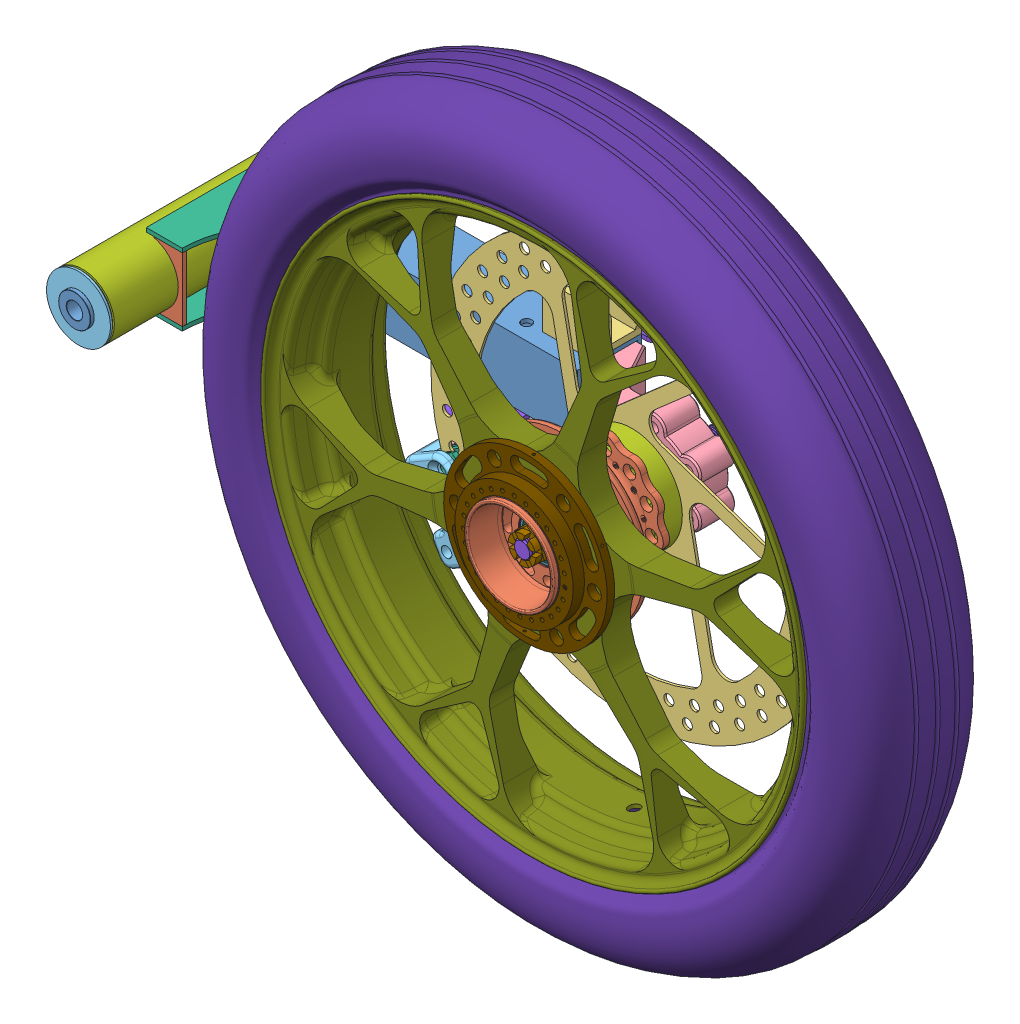
SolidWorks assembly Rear Free Spinning Assembly, configuration Default. Lengths in mm.
Overall size (695.82 635.09 308.21).
71 component instances, 29 part files, 66 mates.
Components (placement in the parent):
- 6338K423_Oil-Embedded Flanged Sleeve Bearing (1)-3: 6338K423_Oil-Embedded Flanged Sleeve Bearing (1) [6338K423] at (-275.5585 98.76 94.6109) size (25.4 25.4 19.05)
- Half Moon Bracket-2: Half Moon Bracket [Default] at (-275.5585 98.76 43.8109) x (1 0 0) z (0 -1 0) size (22.4 3.17 50.8)
- Rear Brake Bracket-2: Rear Brake Bracket [Default] at (-24.3335 128.9225 -60.9641) x (0 0 1) z (1 0 0) size (38.1 36.51 50)
- Rear Cap insert-2: Rear Cap insert [Default] at (-8.8585 76.535 -76.8391) x (0 0 1) z (-1 0 0) size (63.5 83.05 151.54)
- Rear End Cap-3: Rear End Cap [Default] at (-275.5585 98.76 100.9609) x (0 0 -1) z (0.554016 0.832506 0) size (15.88 50.8 50.8)
- Rear Gusset-2: Rear Gusset [Default] at (-50.3286 124.16 -51.4436) x (0 0 1) z (0 1 0) size (127 101.6 3.17)
- Rear Round Tube-2: Rear Round Tube [Default] at (-275.5585 98.76 97.7859) x (0 0 -1) z (1 0 0) size (177.8 50.8 50.8)
- Rear End Cap-4: Rear End Cap [Default] at (-275.5585 98.76 -83.1891) x (0 0 1) z (-0.819378 0.573254 0) size (15.88 50.8 50.8)
- 6338K423_Oil-Embedded Flanged Sleeve Bearing (1)-4: 6338K423_Oil-Embedded Flanged Sleeve Bearing (1) [6338K423] at (-275.5585 98.76 -76.8391) x (-1 0 0) z (0 0 -1) size (25.4 25.4 19.05)
- Longer Spindle_Light-1: Longer Spindle_Light [Default] at (67.3415 98.76 -13.3391) x (0 0 1) z (-0.999407 0.034445 0) size (156.55 34 30)
- 93760A127_Steel Locknut for Use with Cotter Pins-1: 93760A127_Steel Locknut for Use with Cotter Pins [93760A127] at (67.3415 98.76 91.1609) x (0.351034 0.936363 0) z (0 0 1) size (22 25.4 16.76)
- SKF_6004-2Z.stp-2: SKF_6004-2Z.stp [Default] at (67.3415 98.76 29.6609) x (0 0 -1) z (1 0 0) size (12 42 42)
  - SKF_6004-2Z_PART4.stp-1: SKF_6004-2Z_PART4.stp [Default] x (1 0 0) z (0 -0.642788 0.766044)
  - SKF_6004-2Z_PART4.stp-2: SKF_6004-2Z_PART4.stp [Default] x (1 0 0) z (0 -0.984808 0.173648)
  - SKF_6004-2Z_PART4.stp-3: SKF_6004-2Z_PART4.stp [Default] x (1 0 0) z (0 -0.866025 -0.5)
  - SKF_6004-2Z_PART4.stp-4: SKF_6004-2Z_PART4.stp [Default] x (1 0 0) z (0 -0.34202 -0.939693)
  - SKF_6004-2Z_PART4.stp-5: SKF_6004-2Z_PART4.stp [Default] x (1 0 0) z (0 0.34202 -0.939693)
  - SKF_6004-2Z_PART4.stp-6: SKF_6004-2Z_PART4.stp [Default] x (1 0 0) z (0 0.866025 -0.5)
  - SKF_6004-2Z_PART4.stp-7: SKF_6004-2Z_PART4.stp [Default] x (1 0 0) z (0 0.984808 0.173648)
  - SKF_6004-2Z_PART4.stp-8: SKF_6004-2Z_PART4.stp [Default] x (1 0 0) z (0 0.642788 0.766044)
  - SKF_6004-2Z_PART4.stp-9: SKF_6004-2Z_PART4.stp [Default] at origin
  - SKF_6004-2Z_PART3.stp-1: SKF_6004-2Z_PART3.stp [Default] x (1 0 0) z (0 -0.642788 0.766044) size (6.35 6.35 6.35)
  - SKF_6004-2Z_PART3.stp-2: SKF_6004-2Z_PART3.stp [Default] x (1 0 0) z (0 -0.984808 0.173648) size (6.35 6.35 6.35)
  - SKF_6004-2Z_PART3.stp-3: SKF_6004-2Z_PART3.stp [Default] x (1 0 0) z (0 -0.866025 -0.5) size (6.35 6.35 6.35)
  - SKF_6004-2Z_PART3.stp-4: SKF_6004-2Z_PART3.stp [Default] x (1 0 0) z (0 -0.34202 -0.939693) size (6.35 6.35 6.35)
  - SKF_6004-2Z_PART3.stp-5: SKF_6004-2Z_PART3.stp [Default] x (1 0 0) z (0 0.34202 -0.939693) size (6.35 6.35 6.35)
  - SKF_6004-2Z_PART3.stp-6: SKF_6004-2Z_PART3.stp [Default] x (1 0 0) z (0 0.866025 -0.5) size (6.35 6.35 6.35)
  - SKF_6004-2Z_PART3.stp-7: SKF_6004-2Z_PART3.stp [Default] x (1 0 0) z (0 0.984808 0.173648) size (6.35 6.35 6.35)
  - SKF_6004-2Z_PART3.stp-8: SKF_6004-2Z_PART3.stp [Default] x (1 0 0) z (0 0.642788 0.766044) size (6.35 6.35 6.35)
  - SKF_6004-2Z_PART3.stp-9: SKF_6004-2Z_PART3.stp [Default] at origin size (6.35 6.35 6.35)
  - SKF_6004-2Z_PART2.stp-1: SKF_6004-2Z_PART2.stp [Default] at origin size (12 42 42)
  - SKF_6004-2Z_PART1.stp-1: SKF_6004-2Z_PART1.stp [Default] at origin size (12 37.19 37.19)
- SKF_6003-2Z.stp-2: SKF_6003-2Z.stp [Default] at (67.3415 98.76 75.1609) x (0 0 -1) z (-0.882988 0.469396 0) size (10 35 35)
  - SKF_6003-2Z_PART4.stp-1: SKF_6003-2Z_PART4.stp [Default] x (1 0 0) z (0 -0.587785 0.809017)
  - SKF_6003-2Z_PART4.stp-2: SKF_6003-2Z_PART4.stp [Default] x (1 0 0) z (0 -0.951057 0.309017)
  - SKF_6003-2Z_PART4.stp-3: SKF_6003-2Z_PART4.stp [Default] x (1 0 0) z (0 -0.951057 -0.309017)
  - SKF_6003-2Z_PART4.stp-4: SKF_6003-2Z_PART4.stp [Default] x (1 0 0) z (0 -0.587785 -0.809017)
  - SKF_6003-2Z_PART4.stp-5: SKF_6003-2Z_PART4.stp [Default] x (1 0 0) z (0 0 -1)
  - SKF_6003-2Z_PART4.stp-6: SKF_6003-2Z_PART4.stp [Default] x (1 0 0) z (0 0.587785 -0.809017)
  - SKF_6003-2Z_PART4.stp-7: SKF_6003-2Z_PART4.stp [Default] x (1 0 0) z (0 0.951057 -0.309017)
  - SKF_6003-2Z_PART4.stp-8: SKF_6003-2Z_PART4.stp [Default] x (1 0 0) z (0 0.951057 0.309017)
  - SKF_6003-2Z_PART4.stp-9: SKF_6003-2Z_PART4.stp [Default] x (1 0 0) z (0 0.587785 0.809017)
  - SKF_6003-2Z_PART4.stp-10: SKF_6003-2Z_PART4.stp [Default] at origin
  - SKF_6003-2Z_PART3.stp-1: SKF_6003-2Z_PART3.stp [Default] x (1 0 0) z (0 -0.587785 0.809017) size (4.76 4.76 4.76)
  - SKF_6003-2Z_PART3.stp-2: SKF_6003-2Z_PART3.stp [Default] x (1 0 0) z (0 -0.951057 0.309017) size (4.76 4.76 4.76)
  - SKF_6003-2Z_PART3.stp-3: SKF_6003-2Z_PART3.stp [Default] x (1 0 0) z (0 -0.951057 -0.309017) size (4.76 4.76 4.76)
  - SKF_6003-2Z_PART3.stp-4: SKF_6003-2Z_PART3.stp [Default] x (1 0 0) z (0 -0.587785 -0.809017) size (4.76 4.76 4.76)
  - SKF_6003-2Z_PART3.stp-5: SKF_6003-2Z_PART3.stp [Default] x (1 0 0) z (0 0 -1) size (4.76 4.76 4.76)
  - SKF_6003-2Z_PART3.stp-6: SKF_6003-2Z_PART3.stp [Default] x (1 0 0) z (0 0.587785 -0.809017) size (4.76 4.76 4.76)
  - SKF_6003-2Z_PART3.stp-7: SKF_6003-2Z_PART3.stp [Default] x (1 0 0) z (0 0.951057 -0.309017) size (4.76 4.76 4.76)
  - SKF_6003-2Z_PART3.stp-8: SKF_6003-2Z_PART3.stp [Default] x (1 0 0) z (0 0.951057 0.309017) size (4.76 4.76 4.76)
  - SKF_6003-2Z_PART3.stp-9: SKF_6003-2Z_PART3.stp [Default] x (1 0 0) z (0 0.587785 0.809017) size (4.76 4.76 4.76)
  - SKF_6003-2Z_PART3.stp-10: SKF_6003-2Z_PART3.stp [Default] at origin size (4.76 4.76 4.76)
  - SKF_6003-2Z_PART2.stp-1: SKF_6003-2Z_PART2.stp [Default] at origin size (10 35 35)
  - SKF_6003-2Z_PART1.stp-1: SKF_6003-2Z_PART1.stp [Default] at origin size (10 31.2 31.2)
- Mirrorrimmachined v13.2-1: Mirrorrimmachined v13.2 [Default] at (67.3415 98.76 37.3609) x (0 0 1) z (0.757538 0.652791 0) size (93.59 431.57 431.57)
- Michelin Tire-1: Michelin Tire [Default] at (67.3415 98.76 38.6243) x (0 0 -1) z (0.988265 -0.152747 0) size (101.13 556.61 556.61)
- Nut-1: Nut [Default] at (67.3415 98.76 82.4558) x (0.057467 0.998347 0) z (0 0 -1) size (130 130 15.86)
- Rear Torque Tube-3: Rear Torque Tube [Default] at (-8.8585 124.16 -29.2141) x (0 0 -1) z (-1 0 0) size (50.8 50.8 260.35)
- 0Hub5-16-1: 0Hub5-16 [Default] at (67.3415 98.76 41.0778) x (0.896977 0.442077 0) z (-0.442077 0.896977 0) size (130 85 130)
- Large Brake Disk-1: Large Brake Disk [Default] at (67.3415 98.76 3.6609) x (0 0 -1) z (0.946854 -0.321663 0) size (2 320 320)
- Caliper Assembly-2: Caliper Assembly [Default] at (-66.2213 21.6475 -6.8199) x (0.5 -0.866025 0) z (0 0 -1) size (113.01 113.01 50.55)
  - Caliper Assembly.iam-1: Caliper Assembly.iam [Default] at origin size (113.01 113.01 50.55)
    - Caliper A v2.ipt-1: Caliper A v2.ipt [Default] x (-1 0 0) z (0 0 -1) size (69.85 44.45 25.27)
    - Caliper B v9.ipt-1: Caliper B v9.ipt [Default] at origin size (69.85 44.45 25.27)
    - MCP 554 Pads v5.ipt-1: MCP 554 Pads v5.ipt [Default] at (0.0125 -5.95 -15.4307) x (-1 0 0) z (0 0 -1) size (63.75 26 7.7)
    - MCP 554 Pads v5.ipt-2: MCP 554 Pads v5.ipt [Default] at (-0.0125 -5.95 -3.5) size (63.75 26 7.7)
    - MCP FWB caliper mounting bracket v1.ipt-1: MCP FWB caliper mounting bracket v1.ipt [Default] at (-30.8831 -83.23 3.175) x (-0.707107 0.707107 0) z (0 0 -1) size (58.07 101.75 3.36) (hidden)
- Brake Standoff-1: Brake Standoff [Default] at (67.3415 98.76 3.6609) x (-0.751995 -0.659169 0) z (0 0 1) size (80 80 19)
- Left Rear Brake Bracket-2: Left Rear Brake Bracket [Default] at (-61.0622 24.6116 -204.0699) x (-0.5 0.866025 0) z (0 0 1) size (100.49 44.43 197.25)
- Rear Gusset-3: Rear Gusset [Default] at (-50.3286 70.185 -51.4436) x (0 0 1) z (0 1 0) size (127 101.6 3.17)
Mates (geometry in assembly coordinates):
- Concentric14: concentric aligned: cylinder of Rear Round Tube-2 through (-275.5585 98.76 -80.0141) axis (0 0 1) radius 25.4; cylinder of Rear Torque Tube-2 through (-275.5585 98.76 -80.0141) axis (0 0 1) radius 25.4
- Concentric15: concentric aligned: cylinder of Rear End Cap-3 through (-275.5585 98.76 85.0859) axis (0 0 1) radius 22.225; cylinder of Rear Round Tube-2 through (-275.5585 98.76 -80.0141) axis (0 0 1) radius 22.225
- Coincident30: coincident anti-aligned: plane of Rear End Cap-3 through (-275.5585 98.76 97.7859) normal (0 0 -1); plane of Rear Round Tube-2 through (-275.5585 98.76 97.7859) normal (0 0 1)
- Concentric16: concentric anti-aligned: cylinder of Rear Round Tube-2 through (-275.5585 98.76 -80.0141) axis (0 0 1) radius 22.225; cylinder of Rear End Cap-4 through (-275.5585 98.76 -67.3141) axis (0 0 -1) radius 22.225
- Coincident31: coincident anti-aligned: plane of Rear Round Tube-2 through (-275.5585 98.76 -80.0141) normal (0 0 -1); plane of Rear End Cap-4 through (-275.5585 98.76 -80.0141) normal (0 0 1)
- Coincident32: coincident anti-aligned: circle of Rear Round Tube-2; circle of Rear Torque Tube-2
- Coincident33: coincident anti-aligned: plane of Rear Gusset-2 through (-173.9585 124.16 46.9859) normal (0 -1 0); plane of Rear Torque Tube-2 through (-269.2085 124.16 -80.0141) normal (0 1 0)
- Coincident34: coincident aligned: plane of Rear Gusset-2 through (-275.5585 127.335 -80.0141) normal (0 0 -1); plane of Rear Torque Tube-2 through (-269.2085 73.36 -80.0141) normal (0 0 -1)
- Coincident35: coincident anti-aligned: plane of Rear Gusset-2 through (-275.5585 127.335 46.9859) normal (-1 0 0); plane of Rear Round Tube-2 through (-275.5585 98.76 97.7859) normal (1 0 0)
- Concentric17: concentric anti-aligned: cylinder of Half Moon Bracket-2 through (-275.5585 98.76 46.9859) axis (0 0 -1) radius 25.4; cylinder of Rear Round Tube-2 through (-275.5585 98.76 -80.0141) axis (0 0 1) radius 25.4
- Coincident36: coincident: point of Half Moon Bracket-2; point of Rear Gusset-2
- Concentric18: concentric aligned: cylinder of Rear End Cap-4 through (-275.5585 98.76 -67.3141) axis (0 0 -1) radius 9.525; cylinder of 6338K423_Oil-Embedded Flanged Sleeve Bearing (1)-4 through (-275.5585 98.76 -67.3141) axis (0 0 -1) radius 9.5504
- Coincident37: coincident anti-aligned: plane of Rear End Cap-4 through (-275.5585 98.76 -83.1891) normal (0 0 -1); plane of 6338K423_Oil-Embedded Flanged Sleeve Bearing (1)-4 through (-275.5585 98.76 -83.1891) normal (0 0 1)
- Concentric19: concentric aligned: cylinder of 6338K423_Oil-Embedded Flanged Sleeve Bearing (1)-3 through (-275.5585 98.76 85.0859) axis (0 0 1) radius 9.5504; cylinder of Rear End Cap-3 through (-275.5585 98.76 85.0859) axis (0 0 1) radius 9.525
- Coincident39: coincident anti-aligned: plane of 6338K423_Oil-Embedded Flanged Sleeve Bearing (1)-3 through (-275.5585 98.76 100.9609) normal (0 0 -1); plane of Rear End Cap-3 through (-275.5585 98.76 100.9609) normal (0 0 1)
- Coincident40: coincident: line of Rear Brake Bracket-2 through (-49.3335 124.16 -41.9141) axis (0 0 -1); plane of Rear Torque Tube-2 through (-269.2085 124.16 -80.0141) normal (0 1 0)
- Coincident41: coincident: line of Rear Brake Bracket-2 through (-49.3335 124.16 -80.0141) axis (1 0 0); plane of Rear Torque Tube-2 through (-269.2085 73.36 -80.0141) normal (0 0 -1)
- Coincident42: coincident: point of Rear Brake Bracket-2; point of Rear Torque Tube-2
- Coincident43: coincident anti-aligned: plane of Rear Cap insert-2 through (-46.9585 120.985 -76.8391) normal (0 1 0); plane of Rear Torque Tube-2 through (-269.2085 120.985 -76.8391) normal (0 -1 0)
- Coincident44: coincident anti-aligned: plane of Rear Cap insert-2 through (-46.9585 76.535 -76.8391) normal (0 0 -1); plane of Rear Torque Tube-2 through (-269.2085 76.535 -76.8391) normal (0 0 1)
- Coincident46: coincident aligned: line of Rear Cap insert-2 through (-8.8585 77.805 -32.3891) axis (0 1 0); line of Rear Torque Tube-2 through (-8.8585 76.535 -32.3891) axis (0 1 0)
- Concentric20: concentric aligned: cylinder of Rear Cap insert-2 through (67.3415 98.76 -89.5391) axis (0 0 1) radius 10; cylinder of Longer Spindle_Light-1 through (67.3415 98.76 91.1609) axis (0 0 1) radius 10
- Coincident47: coincident anti-aligned: plane of Rear Cap insert-2 through (-8.8585 51.135 -13.3391) normal (0 0 1); plane of Longer Spindle_Light-1 through (67.6859 108.754 -13.3391) normal (0 0 -1)
- Concentric23: concentric aligned: cylinder of Longer Spindle_Light-1 through (67.3415 98.76 91.1609) axis (0 0 1) radius 12; cone of Hub-2 through (137.3345 98.76 29.6609) axis (0 0 1)
- Concentric25: concentric anti-aligned: cylinder of Longer Spindle_Light-1 through (67.3415 98.76 91.1609) axis (0 0 1) radius 8.5; cylinder of SKF_6003-2Z.stp-2/SKF_6003-2Z_PART1.stp-1 through (67.3415 98.76 25.1609) axis (0 0 -1) radius 8.5
- Coincident50: coincident anti-aligned: plane of SKF_6003-2Z.stp-2/SKF_6003-2Z_PART2.stp-1 through (60.0189 84.9854 65.1609) normal (0 0 -1); plane of Hub-2 through (145.0905 85.34 64.6609) normal (0 0 1)
- Concentric26: concentric anti-aligned: circle of 93760A127_Steel Locknut for Use with Cotter Pins-1; circle of SKF_6003-2Z.stp-2/SKF_6003-2Z_PART1.stp-1
- Coincident51: coincident anti-aligned: plane of 93760A127_Steel Locknut for Use with Cotter Pins-1 through (45.64 95.1481 75.1609) normal (0 0 -1); plane of SKF_6003-2Z.stp-2/SKF_6003-2Z_PART1.stp-1 through (61.9716 88.6586 75.1609) normal (0 0 1)
- Concentric27: concentric anti-aligned: cylinder of Hub-2 through (137.3345 98.76 -884.9499) axis (0 0 -1) radius 47; cylinder of Mirrorrimmachined v13.2-1 through (67.3415 98.76 46.4609) axis (0 0 1) radius 47.005
- Coincident52: coincident anti-aligned: plane of Hub-2 through (160.8526 58.0672 59.4689) normal (0 0 1); plane of Mirrorrimmachined v13.2-1 through (93.4531 68.4585 59.6609) normal (0 0 -1)
- Concentric28: concentric anti-aligned: cylinder of Mirrorrimmachined v13.2-1 through (67.3415 98.76 -48.1483) axis (0 0 -1) radius 192.7898; cylinder of Michelin Tire-1 through (67.3415 98.76 141.3472) axis (0 0 1) radius 203
- Concentric29: concentric aligned: circle of Mirrorrimmachined v13.2-1; cylinder of Nut-1 through (67.3415 98.76 32.3009) axis (0 0 -1) radius 65
- Coincident54: coincident anti-aligned: plane of Mirrorrimmachined v13.2-1 through (119.0298 38.7777 82.4558) normal (0 0 1); plane of Nut-1 through (69.3528 133.7021 82.4558) normal (0 0 -1)
- Concentric30: concentric anti-aligned: cylinder of Rear Round Tube-2 through (-275.5585 98.76 -80.0141) axis (0 0 1) radius 25.4; cylinder of Rear Torque Tube-3 through (-275.5585 98.76 -29.2141) axis (0 0 -1) radius 25.4
- Coincident55: coincident anti-aligned: line of Rear Gusset-2 through (-173.9585 124.16 -80.0141) axis (-1 0 0); line of Rear Torque Tube-3 through (-269.2085 124.16 -80.0141) axis (1 0 0)
- Coincident57: coincident: plane of Rear Cap insert-2 through (-46.9585 76.535 -76.8391) normal (0 0 -1); line of Rear Torque Tube-3 through (-8.8585 120.985 -76.8391) axis (0 -1 0)
- Coincident58: coincident: plane of Rear Cap insert-2 through (-46.9585 120.985 -76.8391) normal (0 1 0); line of Rear Torque Tube-3 through (-8.8585 120.985 -32.3891) axis (0 0 -1)
- Coincident60: coincident aligned: line of Rear Brake Bracket-2 through (-49.3335 124.16 -80.0141) axis (1 0 0); line of Rear Torque Tube-3 through (-269.2085 124.16 -80.0141) axis (1 0 0)
- Coincident61: coincident anti-aligned: line of Rear Brake Bracket-2 through (-8.8585 124.16 -80.0141) axis (0 0 1); line of Rear Torque Tube-3 through (-8.8585 124.16 -29.2141) axis (0 0 -1)
- Coincident62: coincident anti-aligned: plane of Rear Cap insert-2 through (-46.9585 76.535 -76.8391) normal (0 -1 0); plane of Rear Torque Tube-3 through (-269.2085 76.535 -32.3891) normal (0 1 0)
- Coincident64: coincident aligned: line of Rear Cap insert-2 through (-8.8585 77.805 -32.3891) axis (0 1 0); line of Rear Torque Tube-3 through (-8.8585 76.535 -32.3891) axis (0 1 0)
- Coincident65: coincident anti-aligned: plane of SKF_6004-2Z.stp-2/SKF_6004-2Z_PART2.stp-1 through (67.3415 119.16 29.6609) normal (0 0 1); plane of 0Hub5-16-1 through (84.384 107.1594 29.6609) normal (0 0 -1)
- Concentric31: concentric anti-aligned: cylinder of Longer Spindle_Light-1 through (67.3415 98.76 91.1609) axis (0 0 1) radius 10; cylinder of 0Hub5-16-1 through (67.3415 98.76 -884.9499) axis (0 0 -1) radius 21
- Coincident66: coincident anti-aligned: plane of Longer Spindle_Light-1 through (67.7548 110.7529 17.6609) normal (0 0 1); plane of SKF_6004-2Z.stp-2/SKF_6004-2Z_PART1.stp-1 through (67.3415 109.36 17.6609) normal (0 0 -1)
- Coincident67: coincident anti-aligned: plane of Mirrorrimmachined v13.2-1 through (93.4531 68.4585 59.6609) normal (0 0 -1); plane of 0Hub5-16-1 through (109.4994 119.5376 59.6609) normal (0 0 1)
- Concentric32: concentric aligned: cylinder of Longer Spindle_Light-1 through (67.3415 98.76 91.1609) axis (0 0 1) radius 12; cylinder of Mirrorrimmachined v13.2-1 through (67.3415 98.76 46.4609) axis (0 0 1) radius 47.005
- Concentric33: concentric anti-aligned: cylinder of 0Hub5-16-1 through (67.3415 98.76 -884.9499) axis (0 0 -1) radius 29; cylinder of Large Brake Disk-1 through (67.3415 98.76 1.6609) axis (0 0 1) radius 30
- Concentric34: concentric aligned: circle of 0Hub5-16-1; circle of Large Brake Disk-1
- Lock1: lock: unknown of Mirrorrimmachined v13.2-1; unknown of 0Hub5-16-1
- Distance1: distance = 0.75 mm anti-aligned: plane of Large Brake Disk-1 through (67.3415 98.76 3.6609) normal (0 0 1); plane of Caliper Assembly-2/Caliper Assembly.iam-1/MCP 554 Pads v5.ipt-1 through (-53.0935 10.8094 4.4109) normal (0 0 -1)
- Tangent1: tangent: plane of Caliper Assembly-2/Caliper Assembly.iam-1/Caliper A v2.ipt-1 through (-54.9728 46.6144 -6.8199) normal (0.866025 0.5 0)
- Coincident71: coincident: plane of Caliper Assembly-2 through (-66.2213 21.6475 -6.8199) normal (0.5 -0.866025 0)
- Distance5: distance = 19 mm anti-aligned: plane of 0Hub5-16-1 through (93.3538 111.5802 22.6609) normal (0 0 -1); plane of Large Brake Disk-1 through (67.3415 98.76 3.6609) normal (0 0 1)
- Lock3: lock: unknown of Mirrorrimmachined v13.2-1; unknown of Nut-1
- Coincident79: coincident anti-aligned: plane of 0Hub5-16-1 through (93.3538 111.5802 22.6609) normal (0 0 -1); plane of Brake Standoff-1 through (67.3415 98.76 22.6609) normal (0 0 1)
- Concentric35: concentric aligned: circle of 0Hub5-16-1; cylinder of Brake Standoff-1 through (67.3415 98.76 22.6609) axis (0 0 -1) radius 30
- Coincident80: coincident aligned: circle of Large Brake Disk-1; cylinder of Brake Standoff-1 through (44.9297 124.3278 22.6609) axis (0 0 -1) radius 2.625
- Coincident81: coincident anti-aligned: plane of Rear Torque Tube-3 through (-269.2085 73.36 -29.2141) normal (0 -1 0); plane of Left Rear Brake Bracket-2 through (-98.2944 73.36 -131.7797) normal (0 1 0)
- Coincident82: coincident anti-aligned: plane of Caliper Assembly-2/Caliper Assembly.iam-1/Caliper A v2.ipt-1 through (-62.0969 24.0287 -9.9949) normal (0 0 1); plane of Left Rear Brake Bracket-2 through (-62.0969 24.0287 -9.9949) normal (0 0 -1)
- Concentric36: concentric anti-aligned: circle of Caliper Assembly-2/Caliper Assembly.iam-1/Caliper A v2.ipt-1; circle of Left Rear Brake Bracket-2
- Coincident83: coincident aligned: plane of Rear Torque Tube-3 through (-269.2085 124.16 -80.0141) normal (0 0 -1); plane of Rear Gusset-3 through (-275.5585 73.36 -80.0141) normal (0 0 -1)
- Coincident84: coincident anti-aligned: plane of Half Moon Bracket-2 through (-275.5585 73.36 46.9859) normal (0 -1 0); plane of Rear Gusset-3 through (-173.9585 73.36 46.9859) normal (0 1 0)
- Coincident85: coincident aligned: plane of Rear Gusset-2 through (-275.5585 127.335 46.9859) normal (-1 0 0); plane of Rear Gusset-3 through (-275.5585 73.36 46.9859) normal (-1 0 0)
- Coincident86: coincident aligned: circle of Rear Round Tube-2; circle of Rear Torque Tube-3
- Coincident87: coincident anti-aligned: plane of SKF_6003-2Z.stp-2/SKF_6003-2Z_PART2.stp-1 through (60.0189 84.9854 65.1609) normal (0 0 -1); plane of 0Hub5-16-1 through (81.2446 105.6122 65.1609) normal (0 0 1)
- Lock4: lock: unknown of Mirrorrimmachined v13.2-1; unknown of Michelin Tire-1
